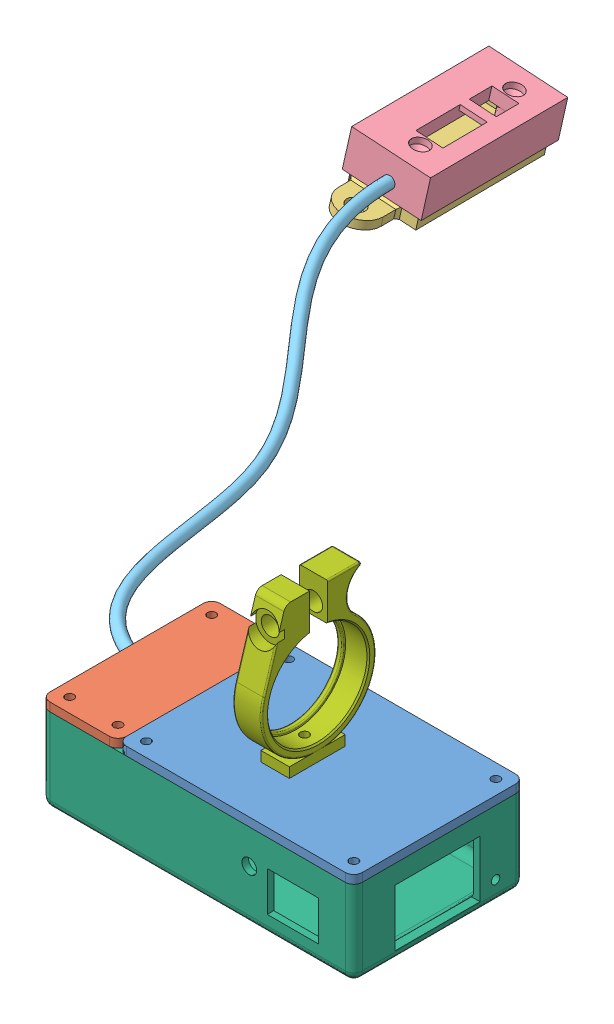
SolidWorks assembly Assem1_Gish, configuration Default. Lengths in mm.
Overall size (274.96 119.43 332.59).
7 component instances, 7 part files, 12 mates.
Components (placement in the parent):
- Part2_Gish-1: Part2_Gish [Default] at (33.4911 47.4992 59.542) size (83 9 60)
- Part2_Gish - Copy3-2: Part2_Gish - Copy3 [Default] at (-21.5089 47.4992 59.542) size (27 3 60)
- housing back v1-1: housing back v1 [Default] at (-186.8847 -4.8839 -203.2161) x (-0.096833 -0.089616 -0.991258) z (-0.142006 -0.984505 0.102878) size (77.46 22.6 7.9)
- housing front v1-1: housing front v1 [Default] at (-185.8514 3.792 -204.3031) x (-0.096833 -0.089616 -0.991258) z (0.142006 0.984505 -0.102878) size (54 26 13.5)
- Part4-1: Part4 [Default] at (-89.7792 5.8707 -129.7799) x (-0.241029 -0.087385 -0.966576) z (0.970518 -0.021702 -0.24005) size (244.35 4 93.44)
- Part_Gish-3: Part_Gish [Default] at (19.9911 17.4992 59.542) size (110 30 60)
- holder-1: holder [По умолчанию] at (28.4911 73.6668 60.4164) x (0 -1 0) z (0 0 1) size (53.57 10.32 40.2)
Mates (geometry in assembly coordinates):
- Coincident6: coincident anti-aligned: plane of Part2_Gish-1 through (33.4911 50.4992 59.542) normal (0 1 0); plane of Зажим 35 мм-1 through (29.781 50.4992 70.122) normal (0 -1 0)
- Coincident12: coincident anti-aligned: plane of housing back v1-1 through (-184.759 56.2148 -183.4243) normal (-0.985118 0.150726 0.082606); plane of housing front v1-1 through (-192.6428 1.5573 -177.7128) normal (0.985118 -0.150726 -0.082606)
- Coincident13: coincident anti-aligned: plane of housing back v1-1 through (-162.4953 52.8084 -185.2912) normal (0.096833 0.089616 0.991258); plane of housing front v1-1 through (-169.9851 -1.9094 -179.6127) normal (-0.096833 -0.089616 -0.991258)
- Coincident14: coincident anti-aligned: plane of housing back v1-1 through (-181.0547 -2.8578 -203.9687) normal (0.142006 0.984505 -0.102878); plane of housing front v1-1 through (-186.6893 -2.0166 -203.6961) normal (-0.142006 -0.984505 0.102878)
- Coincident22: coincident anti-aligned: line of Part2_Gish-1 through (-8.0089 50.4992 32.542) axis (0 0 1); line of Part2_Gish - Copy3-2 through (-8.0089 50.4992 86.542) axis (0 0 -1)
- Coincident24: coincident aligned: line of Part2_Gish - Copy3-2 through (-35.0089 47.4992 32.542) axis (0 0 1); line of Part_Gish-3 through (-35.0089 47.4992 32.542) axis (0 0 1)
- Coincident25: coincident aligned: line of Part2_Gish-1 through (7.965 47.4992 89.542) axis (1 0 0); line of Part_Gish-3 through (-32.0089 47.4992 89.542) axis (1 0 0)
- Concentric2: concentric aligned: circle of Part4-1; circle of Part_Gish-3
- Coincident29: coincident anti-aligned: plane of housing front v1-1 through (-158.3602 67.3409 -185.4958) normal (0.096833 0.089616 0.991258); plane of Part4-1 through (-179.7321 1.56 -177.461) normal (-0.096833 -0.089616 -0.991258)
- Coincident30: coincident anti-aligned: plane of Part2_Gish-1 through (33.4911 50.4992 59.542) normal (0 1 0); plane of holder-1 through (33.4911 50.4992 70.7191) normal (0 -1 0)
- Coincident31: coincident anti-aligned: plane of Part2_Gish-1 through (33.4911 50.4992 59.542) normal (0 1 0); plane of holder-1 through (33.4911 50.4992 70.7191) normal (0 -1 0)
- Coincident32: coincident aligned: line of Part2_Gish-1 through (33.4911 50.4992 53.9409) axis (0 0 1); line of holder-1 through (33.4911 50.4992 51.084) axis (0 0 1)
